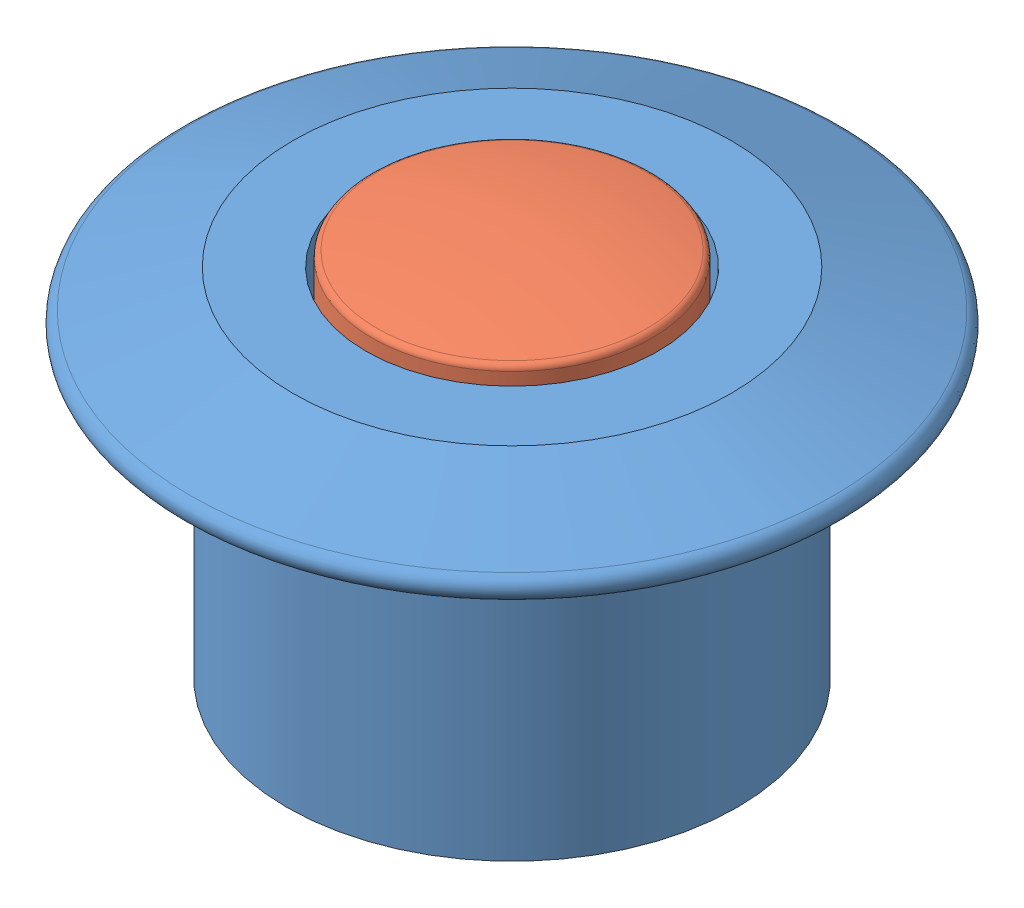
SolidWorks assembly pin lock top assembly, configuration Default. Lengths in mm.
Overall size (58.84 54.6 54.16).
2 component instances, 2 part files, 2 mates.
Components (placement in the parent):
- head-1: head [Default] at (20.8409 27.2426 41.9364) size (58.84 54.6 54.16)
- button-1: button [Default] at (20.8409 34.5168 41.9364) x (0.997003 0 -0.077357) z (0.077357 0 0.997003) size (23 21.19 23)
Mates (geometry in assembly coordinates):
- Concentric1: concentric anti-aligned: cylinder of head-1 through (20.8409 3.0316 41.9364) axis (0 1 0) radius 12; cylinder of button-1 through (20.8409 13.347 41.9364) axis (0 -1 0) radius 11.5
- Lock1: lock: unknown of head-1; unknown of button-1
